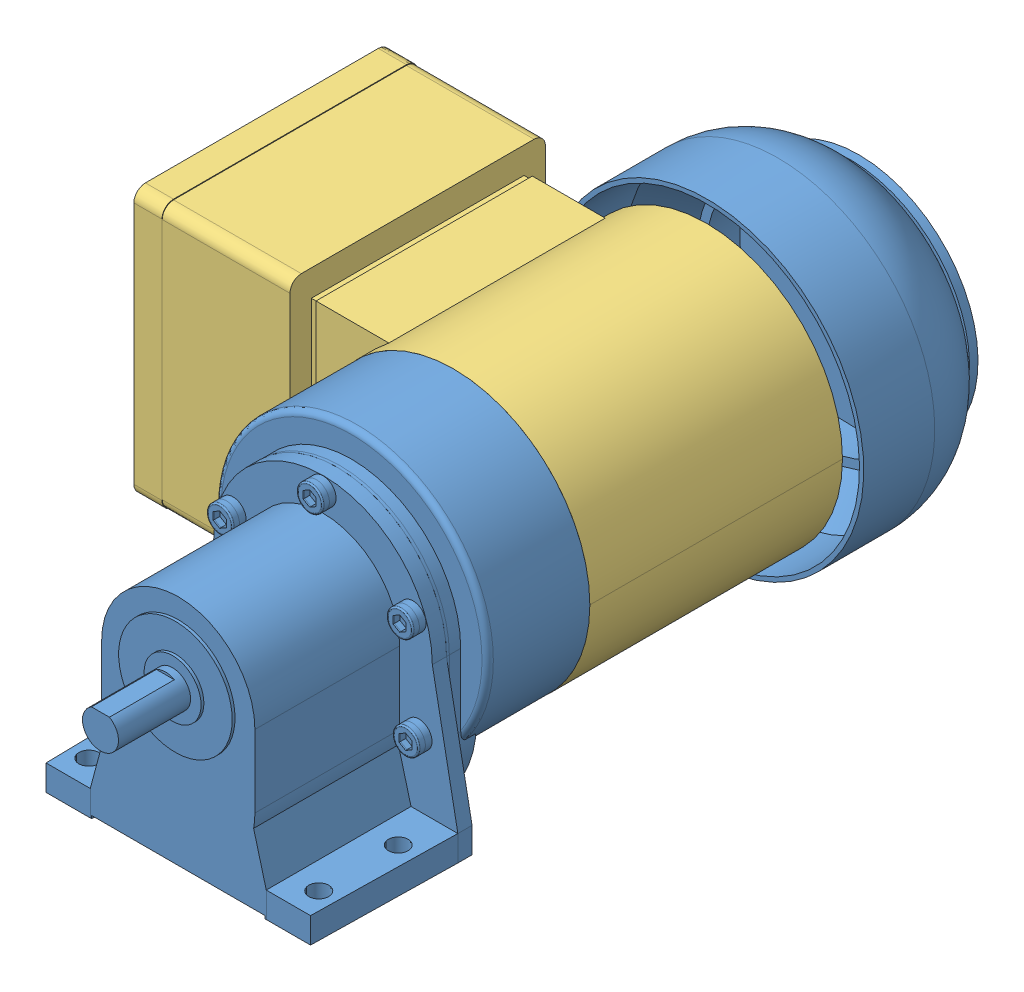
SolidWorks assembly VL Motion-VLH04T0442365IIIAS, configuration Default. Lengths in mm.
Overall size (167.62 111.25 267.15).
3 component instances, 3 part files, 9 mates.
Components (placement in the parent):
- VL Motion-VLH04T0442365IIIAS_VLH04T04-1: VL Motion-VLH04T0442365IIIAS_VLH04T04 [Default] at (0 0 -26.4) x (0 0 -1) z (1 0 0) size (267.15 111.25 110.5)
- VL Motion-VLH04T0442365IIIAS_logo-1: VL Motion-VLH04T0442365IIIAS_logo [Default] at (0.9525 -6.5967 -213.2599) x (0 0 1) z (-1 0 0) size (52.7 9.89 0.32)
- VL Motion-VLH04T0442365IIIAS_a_D04-03-KK1-1: VL Motion-VLH04T0442365IIIAS_a_D04-03-KK1 [Default] at (0 0 -124.4) x (0 0 -1) z (-1 0 0) size (90.17 96 160.06)
Mates (geometry in assembly coordinates):
- Coincident6: coincident: plane of assembly through (0 0 0) normal (0 0 1); plane of VL Motion-VLH04T0442365IIIAS_VLH04T04-1 through (0 0 0) normal (0 0 1)
- Parallel8: parallel: plane of assembly through (0 0 0) normal (0 1 0); plane of VL Motion-VLH04T0442365IIIAS_VLH04T04-1 through (0 -47 -26.4) normal (0 1 0)
- Concentric3: concentric: line of assembly; cylinder of VL Motion-VLH04T0442365IIIAS_VLH04T04-1 through (0 0 0) axis (0 0 -1) radius 6.35
- Concentric14: concentric: line of assembly; cylinder of VL Motion-VLH04T0442365IIIAS_a_D04-03-KK1-1 through (0 0 -213.4) axis (0 0 1) radius 48
- Coincident14: coincident: line of assembly; point of VL Motion-VLH04T0442365IIIAS_a_D04-03-KK1-1
- Coincident15: coincident: plane of VL Motion-VLH04T0442365IIIAS_VLH04T04-1 through (48 0 -124.4) normal (0 0 -1); plane of VL Motion-VLH04T0442365IIIAS_a_D04-03-KK1-1 through (48.576 48.576 -124.4) normal (0 0 1)
- Coincident16: coincident: plane of VL Motion-VLH04T0442365IIIAS_logo-1 through (-112.056 -6.5967 -213.2599) normal (1 0 0); plane of VL Motion-VLH04T0442365IIIAS_a_D04-03-KK1-1 through (-112.056 46.99 -123.815) normal (-1 0 0)
- Coincident17: coincident: line of VL Motion-VLH04T0442365IIIAS_logo-1 through (-112.056 46.99 -142.5638) axis (0 0 -1); line of VL Motion-VLH04T0442365IIIAS_a_D04-03-KK1-1 through (-112.056 46.99 -127.879) axis (0 0 -1)
- Coincident19: coincident: point of VL Motion-VLH04T0442365IIIAS_logo-1; moEndPointRef_w of VL Motion-VLH04T0442365IIIAS_a_D04-03-KK1-1
